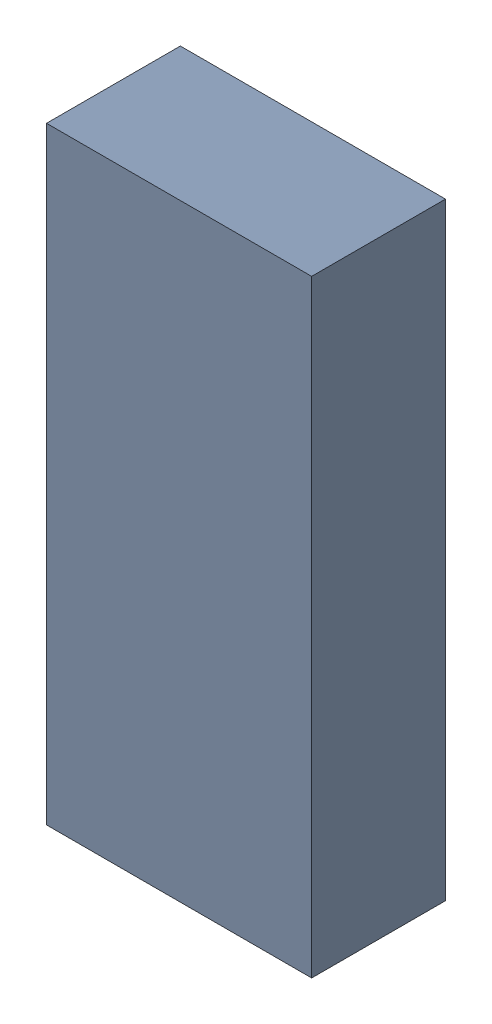
SolidWorks assembly 6327397312, configuration Default. Lengths in mm.
Overall size (0.5 1.15 0.25).
2 component instances, 1 part files, 0 mates.
Components (placement in the parent):
- 6701982208-1:  [Default] at (27.7 14.8 0) (suppressed, hidden)
- Extruded-4-1: Extruded-4 [Default] at origin size (0.5 1.15 0.25)
